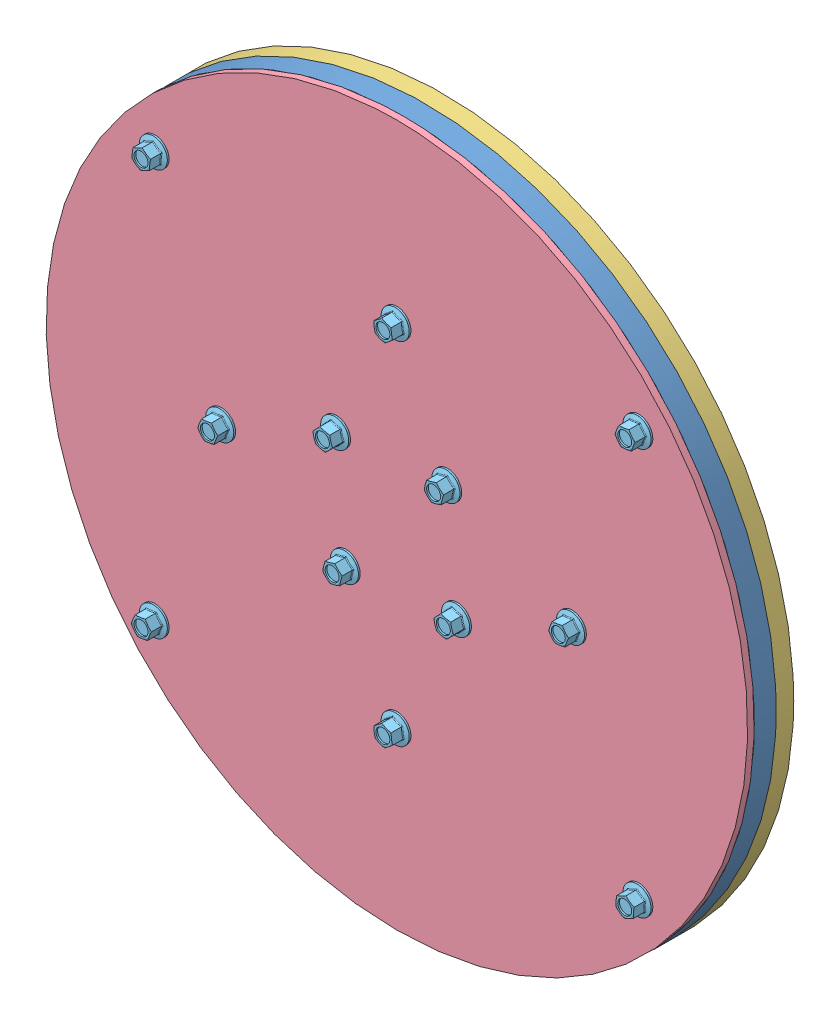
SolidWorks assembly Magnitic gear Assem, configuration Default. Lengths in mm.
Overall size (160 160 29.7).
42 component instances, 7 part files, 35 mates.
Components (placement in the parent):
- Magnitic Disk-1: Magnitic Disk [Default] at (41.0796 91.4557 127.2448) size (160 160 5)
- Disk holder-1: Disk holder [Default] at (41.0796 91.4557 107.2448) x (0.766044 0.642788 0) z (0 0 1) size (50 50 20)
- Magnet Back limit-1: Magnet Back limit [Default] at (41.0796 91.4557 123.2448) size (160 160 4)
- magnetic gear cover-1: magnetic gear cover [Default] at (41.0796 91.4557 132.2448) x (0 1 0) z (0 0 1) size (160 160 1.5)
- indented hex flange head machine screw_am-1: indented hex flange head machine screw_am [AM B18.6.7M 3x13-12-N] at (96.2348 137.7364 133.7448) x (0 0 -1) z (0.924187 -0.38194 0) size (16.2 6.4 6.4)
- indented hex flange head machine screw_am-2: indented hex flange head machine screw_am [AM B18.6.7M 3x13-12-N] at (-14.0756 45.175 133.7448) x (0 0 -1) z (-0.924187 0.38194 0) size (16.2 6.4 6.4)
- indented hex flange head machine screw_am-3: indented hex flange head machine screw_am [AM B18.6.7M 3x13-12-N] at (-14.0756 137.7364 133.7448) x (0 0 -1) z (-0.569202 -0.822198 0) size (16.2 6.4 6.4)
- indented hex flange head machine screw_am-4: indented hex flange head machine screw_am [AM B18.6.7M 3x13-12-N] at (96.2348 45.175 133.7448) x (0 0 -1) z (0.569202 0.822198 0) size (16.2 6.4 6.4)
- indented hex flange head machine screw_am-5: indented hex flange head machine screw_am [AM B18.6.7M 3x13-12-N] at (81.0796 91.4557 133.7448) x (0 0 -1) z (0.149948 -0.988694 0) size (16.2 6.4 6.4)
- indented hex flange head machine screw_am-6: indented hex flange head machine screw_am [AM B18.6.7M 3x13-12-N] at (41.0796 131.4557 133.7448) x (0 0 -1) z (0.988694 0.149948 0) size (16.2 6.4 6.4)
- indented hex flange head machine screw_am-7: indented hex flange head machine screw_am [AM B18.6.7M 3x13-12-N] at (1.0796 91.4557 133.7448) x (0 0 -1) z (-0.149948 0.988694 0) size (16.2 6.4 6.4)
- indented hex flange head machine screw_am-8: indented hex flange head machine screw_am [AM B18.6.7M 3x13-12-N] at (41.0796 51.4557 133.7448) x (0 0 -1) z (-0.988694 -0.149948 0) size (16.2 6.4 6.4)
- indented hex flange head machine screw_am-9: indented hex flange head machine screw_am [AM B18.6.7M 3x13-12-N] at (52.6497 105.2445 133.7448) x (0 0 -1) z (0.276974 -0.960877 0) size (16.2 6.4 6.4)
- indented hex flange head machine screw_am-10: indented hex flange head machine screw_am [AM B18.6.7M 3x13-12-N] at (27.2908 103.0259 133.7448) x (0 0 -1) z (0.960877 0.276974 0) size (16.2 6.4 6.4)
- indented hex flange head machine screw_am-11: indented hex flange head machine screw_am [AM B18.6.7M 3x13-12-N] at (29.5094 77.6669 133.7448) x (0 0 -1) z (-0.276974 0.960877 0) size (16.2 6.4 6.4)
- indented hex flange head machine screw_am-12: indented hex flange head machine screw_am [AM B18.6.7M 3x13-12-N] at (54.8684 79.8855 133.7448) x (0 0 -1) z (-0.960877 -0.276974 0) size (16.2 6.4 6.4)
- hex nut style 2_am-1: hex nut style 2_am [B18.2.4.2M - Hex nut, Style 2,  M3 x 0.5 --D-N] at (41.0796 131.4557 120.3448) x (0.923728 0.383049 0) z (0 0 -1) size (5.5 6.35 2.9)
- hex nut style 2_am-2: hex nut style 2_am [B18.2.4.2M - Hex nut, Style 2,  M3 x 0.5 --D-N] at (1.0796 91.4557 120.3448) x (0.923728 0.383049 0) z (0 0 -1) size (5.5 6.35 2.9)
- hex nut style 2_am-3: hex nut style 2_am [B18.2.4.2M - Hex nut, Style 2,  M3 x 0.5 --D-N] at (-14.0756 137.7364 120.3448) x (0.923728 0.383049 0) z (0 0 -1) size (5.5 6.35 2.9)
- hex nut style 2_am-4: hex nut style 2_am [B18.2.4.2M - Hex nut, Style 2,  M3 x 0.5 --D-N] at (-14.0756 45.175 120.3448) x (0.923728 0.383049 0) z (0 0 -1) size (5.5 6.35 2.9)
- hex nut style 2_am-5: hex nut style 2_am [B18.2.4.2M - Hex nut, Style 2,  M3 x 0.5 --D-N] at (41.0796 51.4557 120.3448) x (0.923728 0.383049 0) z (0 0 -1) size (5.5 6.35 2.9)
- hex nut style 2_am-6: hex nut style 2_am [B18.2.4.2M - Hex nut, Style 2,  M3 x 0.5 --D-N] at (81.0796 91.4557 120.3448) x (0.923728 0.383049 0) z (0 0 -1) size (5.5 6.35 2.9)
- hex nut style 2_am-8: hex nut style 2_am [B18.2.4.2M - Hex nut, Style 2,  M3 x 0.5 --D-N] at (96.2348 137.7364 120.3448) x (0.923728 0.383049 0) z (0 0 -1) size (5.5 6.35 2.9)
- hex nut style 2_am-9: hex nut style 2_am [B18.2.4.2M - Hex nut, Style 2,  M3 x 0.5 --D-N] at (96.2348 45.175 120.3448) x (0.923728 0.383049 0) z (0 0 -1) size (5.5 6.35 2.9)
- Magnet-1: Magnet [Default] at (61.6008 147.8373 127.2448) x (0.939693 -0.34202 0) z (-0.34202 -0.939693 0) size (10 5 20)
- Magnet-2: Magnet [Default] at (41.0796 151.4557 127.2448) x (1 0 0) z (0 -1 0) size (10 5 20)
- Magnet-3: Magnet [Default] at (20.5584 147.8373 127.2448) x (0.939693 0.34202 0) z (0.34202 -0.939693 0) size (10 5 20)
- Magnet-4: Magnet [Default] at (2.5123 137.4184 127.2448) x (0.766044 0.642788 0) z (0.642788 -0.766044 0) size (10 5 20)
- Magnet-5: Magnet [Default] at (-10.882 121.4557 127.2448) x (0.5 0.866025 0) z (0.866025 -0.5 0) size (10 5 20)
- Magnet-6: Magnet [Default] at (-18.0089 101.8746 127.2448) x (0.173648 0.984808 0) z (0.984808 -0.173648 0) size (10 5 20)
- Magnet-7: Magnet [Default] at (-18.0089 81.0368 127.2448) x (-0.173648 0.984808 0) z (0.984808 0.173648 0) size (10 5 20)
- Magnet-8: Magnet [Default] at (-10.882 61.4557 127.2448) x (-0.5 0.866025 0) z (0.866025 0.5 0) size (10 5 20)
- Magnet-9: Magnet [Default] at (2.5123 45.493 127.2448) x (-0.766044 0.642788 0) z (0.642788 0.766044 0) size (10 5 20)
- Magnet-10: Magnet [Default] at (20.5584 35.0741 127.2448) x (-0.939693 0.34202 0) z (0.34202 0.939693 0) size (10 5 20)
- Magnet-11: Magnet [Default] at (41.0796 31.4557 127.2448) x (-1 0 0) z (0 1 0) size (10 5 20)
- Magnet-12: Magnet [Default] at (61.6008 35.0741 127.2448) x (-0.939693 -0.34202 0) z (-0.34202 0.939693 0) size (10 5 20)
- Magnet-13: Magnet [Default] at (79.6468 45.493 127.2448) x (-0.766044 -0.642788 0) z (-0.642788 0.766044 0) size (10 5 20)
- Magnet-14: Magnet [Default] at (93.0411 61.4557 127.2448) x (-0.5 -0.866025 0) z (-0.866025 0.5 0) size (10 5 20)
- Magnet-15: Magnet [Default] at (100.168 81.0368 127.2448) x (-0.173648 -0.984808 0) z (-0.984808 0.173648 0) size (10 5 20)
- Magnet-16: Magnet [Default] at (100.168 101.8746 127.2448) x (0.173648 -0.984808 0) z (-0.984808 -0.173648 0) size (10 5 20)
- Magnet-17: Magnet [Default] at (93.0411 121.4557 127.2448) x (0.5 -0.866025 0) z (-0.866025 -0.5 0) size (10 5 20)
- Magnet-18: Magnet [Default] at (79.6468 137.4184 127.2448) x (0.766044 -0.642788 0) z (-0.642788 -0.766044 0) size (10 5 20)
Mates (geometry in assembly coordinates):
- Concentric1: concentric anti-aligned: cylinder of Magnitic Disk-1 through (41.0796 91.4557 127.2448) axis (0 0 1) radius 4; cylinder of Disk holder-1 through (41.0796 91.4557 127.2448) axis (0 0 -1) radius 4
- Coincident1: coincident anti-aligned: plane of Magnitic Disk-1 through (41.0796 91.4557 127.2448) normal (0 0 -1); plane of Disk holder-1 through (41.0796 91.4557 127.2448) normal (0 0 1)
- Coincident2: coincident anti-aligned: plane of Magnitic Disk-1 through (41.0796 91.4557 127.2448) normal (0 0 -1); plane of Magnet Back limit-1 through (41.0796 91.4557 127.2448) normal (0 0 1)
- Concentric5: concentric aligned: cylinder of Magnitic Disk-1 through (41.0796 91.4557 132.2448) axis (0 0 -1) radius 80; cylinder of magnetic gear cover-1 through (41.0796 91.4557 133.7448) axis (0 0 -1) radius 80
- Concentric9: concentric aligned: cylinder of Magnitic Disk-1 through (41.0796 91.4557 132.2448) axis (0 0 -1) radius 80; cylinder of Magnet Back limit-1 through (41.0796 91.4557 127.2448) axis (0 0 -1) radius 80
- Concentric10: concentric anti-aligned: cylinder of Magnitic Disk-1 through (-14.0756 45.175 127.2448) axis (0 0 1) radius 1.6; cylinder of Magnet Back limit-1 through (-14.0756 45.175 127.2448) axis (0 0 -1) radius 2.6
- Coincident7: coincident anti-aligned: plane of Magnitic Disk-1 through (41.0796 91.4557 132.2448) normal (0 0 1); plane of magnetic gear cover-1 through (41.0796 91.4557 132.2448) normal (0 0 -1)
- Concentric11: concentric anti-aligned: cylinder of Magnitic Disk-1 through (-14.0756 137.7364 127.2448) axis (0 0 1) radius 1.6; cylinder of magnetic gear cover-1 through (-14.0756 137.7364 133.7448) axis (0 0 -1) radius 2.6
- Concentric12: concentric aligned: cylinder of Magnitic Disk-1 through (96.2348 137.7364 127.2448) axis (0 0 1) radius 1.6; cylinder of AM B18.6.7M 3x13-12-N-1 through (96.2348 137.7364 136.5448) axis (0 0 1) radius 1.5
- Coincident9: coincident anti-aligned: plane of magnetic gear cover-1 through (41.0796 91.4557 133.7448) normal (0 0 1); plane of AM B18.6.7M 3x13-12-N-1 through (96.8459 139.2151 133.7448) normal (0 0 -1)
- Concentric13: concentric aligned: cylinder of Magnitic Disk-1 through (-14.0756 137.7364 127.2448) axis (0 0 1) radius 1.6; cylinder of AM B18.6.7M 3x13-12-N-3 through (-14.0756 137.7364 136.5448) axis (0 0 1) radius 1.5
- Coincident10: coincident anti-aligned: plane of magnetic gear cover-1 through (41.0796 91.4557 133.7448) normal (0 0 1); plane of AM B18.6.7M 3x13-12-N-3 through (-12.7601 136.8257 133.7448) normal (0 0 -1)
- Concentric14: concentric aligned: cylinder of Magnitic Disk-1 through (81.0796 91.4557 127.2448) axis (0 0 1) radius 1.6; cylinder of AM B18.6.7M 3x13-12-N-5 through (81.0796 91.4557 136.5448) axis (0 0 1) radius 1.5
- Coincident11: coincident anti-aligned: plane of magnetic gear cover-1 through (41.0796 91.4557 133.7448) normal (0 0 1); plane of AM B18.6.7M 3x13-12-N-5 through (82.6615 91.6956 133.7448) normal (0 0 -1)
- Concentric15: concentric anti-aligned: cylinder of magnetic gear cover-1 through (52.6497 105.2445 142.2448) axis (0 0 -1) radius 2.6; cylinder of AM B18.6.7M 3x13-12-N-9 through (52.6497 105.2445 136.5448) axis (0 0 1) radius 1.5
- Coincident12: coincident anti-aligned: plane of magnetic gear cover-1 through (41.0796 91.4557 133.7448) normal (0 0 1); plane of AM B18.6.7M 3x13-12-N-9 through (54.1871 105.6877 133.7448) normal (0 0 -1)
- Concentric161: concentric aligned: cylinder of Magnet Back limit-1 through (41.0796 131.4557 127.2448) axis (0 0 -1) radius 2.6; cylinder of B18.2.4.2M - Hex nut, Style 2,  M3 x 0.5 --D-N-1 through (41.0796 131.4557 145.3823) axis (0 0 -1) radius 1.5
- Coincident131: coincident anti-aligned: plane of Magnet Back limit-1 through (41.0796 91.4557 123.2448) normal (0 0 -1); plane of B18.2.4.2M - Hex nut, Style 2,  M3 x 0.5 --D-N-1 through (42.2959 128.5225 123.2448) normal (0 0 1)
- Concentric171: concentric aligned: cylinder of Magnet Back limit-1 through (1.0796 91.4557 127.2448) axis (0 0 -1) radius 2.6; cylinder of B18.2.4.2M - Hex nut, Style 2,  M3 x 0.5 --D-N-2 through (1.0796 91.4557 145.3823) axis (0 0 -1) radius 1.5
- Coincident141: coincident anti-aligned: plane of Magnet Back limit-1 through (41.0796 91.4557 123.2448) normal (0 0 -1); plane of B18.2.4.2M - Hex nut, Style 2,  M3 x 0.5 --D-N-2 through (2.2959 88.5225 123.2448) normal (0 0 1)
- Concentric181: concentric anti-aligned: cylinder of AM B18.6.7M 3x13-12-N-3 through (-14.0756 137.7364 136.5448) axis (0 0 1) radius 1.5; cylinder of B18.2.4.2M - Hex nut, Style 2,  M3 x 0.5 --D-N-3 through (-14.0756 137.7364 145.3823) axis (0 0 -1) radius 1.5
- Coincident151: coincident anti-aligned: plane of Magnet Back limit-1 through (41.0796 91.4557 123.2448) normal (0 0 -1); plane of B18.2.4.2M - Hex nut, Style 2,  M3 x 0.5 --D-N-3 through (-12.8593 134.8032 123.2448) normal (0 0 1)
- Concentric191: concentric aligned: cylinder of Magnet Back limit-1 through (-14.0756 45.175 127.2448) axis (0 0 -1) radius 2.6; cylinder of B18.2.4.2M - Hex nut, Style 2,  M3 x 0.5 --D-N-4 through (-14.0756 45.175 145.3823) axis (0 0 -1) radius 1.5
- Coincident161: coincident anti-aligned: plane of Magnet Back limit-1 through (41.0796 91.4557 123.2448) normal (0 0 -1); plane of B18.2.4.2M - Hex nut, Style 2,  M3 x 0.5 --D-N-4 through (-12.8593 42.2418 123.2448) normal (0 0 1)
- Concentric201: concentric aligned: cylinder of Magnet Back limit-1 through (41.0796 51.4557 127.2448) axis (0 0 -1) radius 2.6; cylinder of B18.2.4.2M - Hex nut, Style 2,  M3 x 0.5 --D-N-5 through (41.0796 51.4557 145.3823) axis (0 0 -1) radius 1.5
- Coincident171: coincident anti-aligned: plane of Magnet Back limit-1 through (41.0796 91.4557 123.2448) normal (0 0 -1); plane of B18.2.4.2M - Hex nut, Style 2,  M3 x 0.5 --D-N-5 through (42.2959 48.5225 123.2448) normal (0 0 1)
- Concentric211: concentric anti-aligned: cylinder of AM B18.6.7M 3x13-12-N-5 through (81.0796 91.4557 136.5448) axis (0 0 1) radius 1.5; cylinder of B18.2.4.2M - Hex nut, Style 2,  M3 x 0.5 --D-N-6 through (81.0796 91.4557 145.3823) axis (0 0 -1) radius 1.5
- Coincident181: coincident anti-aligned: plane of Magnet Back limit-1 through (41.0796 91.4557 123.2448) normal (0 0 -1); plane of B18.2.4.2M - Hex nut, Style 2,  M3 x 0.5 --D-N-6 through (82.2959 88.5225 123.2448) normal (0 0 1)
- Concentric221: concentric anti-aligned: cylinder of AM B18.6.7M 3x13-12-N-1 through (96.2348 137.7364 136.5448) axis (0 0 1) radius 1.5; cylinder of B18.2.4.2M - Hex nut, Style 2,  M3 x 0.5 --D-N-8 through (96.2348 137.7364 145.3823) axis (0 0 -1) radius 1.5
- Coincident191: coincident anti-aligned: plane of Magnet Back limit-1 through (41.0796 91.4557 123.2448) normal (0 0 -1); plane of B18.2.4.2M - Hex nut, Style 2,  M3 x 0.5 --D-N-8 through (97.4511 134.8032 123.2448) normal (0 0 1)
- Concentric231: concentric aligned: cylinder of Magnet Back limit-1 through (96.2348 45.175 127.2448) axis (0 0 -1) radius 2.6; cylinder of B18.2.4.2M - Hex nut, Style 2,  M3 x 0.5 --D-N-9 through (96.2348 45.175 145.3823) axis (0 0 -1) radius 1.5
- Coincident201: coincident anti-aligned: plane of Magnet Back limit-1 through (41.0796 91.4557 123.2448) normal (0 0 -1); plane of B18.2.4.2M - Hex nut, Style 2,  M3 x 0.5 --D-N-9 through (97.4511 42.2418 123.2448) normal (0 0 1)
- Coincident202: coincident anti-aligned: plane of magnetic gear cover-1 through (41.0796 91.4557 132.2448) normal (0 0 -1); plane of Magnet-1 through (61.6008 147.8373 132.2448) normal (0 0 1)
- Coincident203: coincident anti-aligned: plane of Magnitic Disk-1 through (62.879 136.7302 127.2448) normal (-0.939693 0.34202 0); plane of Magnet-1 through (62.879 136.7302 132.2448) normal (0.939693 -0.34202 0)
- Coincident204: coincident anti-aligned: plane of Magnitic Disk-1 through (53.4821 140.1504 127.2448) normal (0.34202 0.939693 0); plane of Magnet-1 through (62.879 136.7302 132.2448) normal (-0.34202 -0.939693 0)
